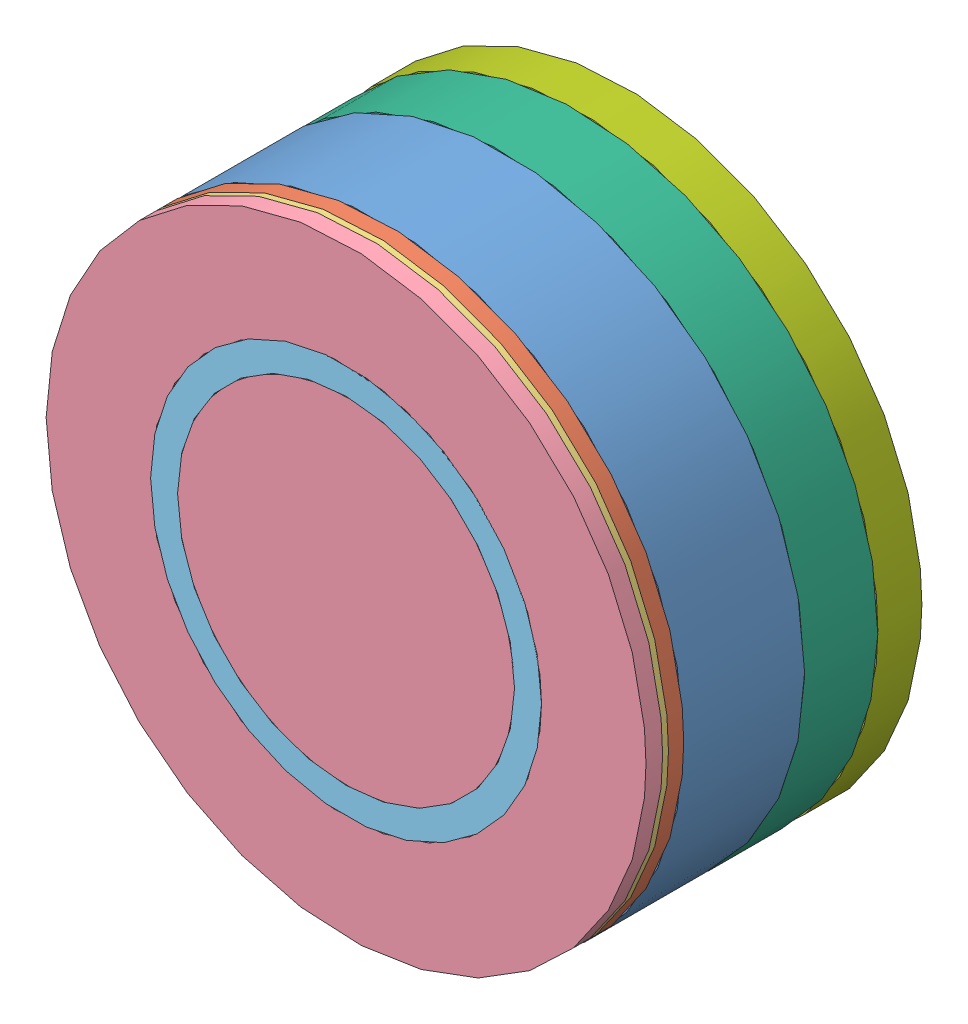
SolidWorks assembly ETA_3, configuration Default. Lengths in mm.
Overall size (348.91 348.91 122.8).
7 component instances, 7 part files, 12 mates.
Components (placement in the parent):
- B_m-2: B_m [Default] at (144.8274 154.4854 158.683) size (267 267 53.8)
- Ba_m-3: Ba_m [Default] at (144.8274 154.4854 212.483) size (267 267 6.8)
- Pr_m-2: Pr_m [Default] at (144.8274 154.4854 219.283) size (267 267 2.6)
- Bi_4_m-2: Bi_4_m [Default] at (144.8274 154.4854 221.883) size (267 267 7.4)
- Si_3-2: Si_3 [Default] at (144.8274 154.4854 148.183) size (174 174 81.1)
- Cr_m-1: Cr_m [Default] at (144.8274 154.4854 158.683) x (-0.923728 -0.383049 0) z (0 0 -1) size (267 267 38.1)
- Al-1: Al [Default] at (144.8274 154.4854 106.483) size (267 267 19.6)
Mates (geometry in assembly coordinates):
- Coincident29: coincident anti-aligned: plane of B_m-2 through (144.8274 154.4854 212.483) normal (0 0 1); plane of Ba_m-3 through (144.8274 154.4854 212.483) normal (0 0 -1)
- Coincident30: coincident aligned: circle of B_m-2; circle of Ba_m-3
- Coincident31: coincident anti-aligned: plane of Ba_m-3 through (144.8274 154.4854 219.283) normal (0 0 1); plane of Pr_m-2 through (144.8274 154.4854 219.283) normal (0 0 -1)
- Coincident32: coincident aligned: circle of Ba_m-3; circle of Pr_m-2
- Coincident33: coincident anti-aligned: plane of Pr_m-2 through (144.8274 154.4854 221.883) normal (0 0 1); plane of Bi_4_m-2 through (144.8274 154.4854 221.883) normal (0 0 -1)
- Coincident34: coincident aligned: circle of Pr_m-2; circle of Bi_4_m-2
- Coincident35: coincident aligned: plane of Bi_4_m-2 through (144.8274 154.4854 229.283) normal (0 0 1); plane of Si_3-2 through (144.8274 154.4854 229.283) normal (0 0 1)
- Coincident36: coincident aligned: circle of Bi_4_m-2; circle of Si_3-2
- Coincident37: coincident anti-aligned: plane of B_m-2 through (144.8274 154.4854 158.683) normal (0 0 -1); plane of Cr_m-1 through (144.8274 154.4854 158.683) normal (0 0 1)
- Coincident38: coincident anti-aligned: circle of B_m-2; circle of Cr_m-1
- Coincident39: coincident anti-aligned: plane of Cr_m-1 through (144.8274 154.4854 126.083) normal (0 0 -1); plane of Al-1 through (144.8274 154.4854 126.083) normal (0 0 1)
- Coincident40: coincident anti-aligned: circle of Cr_m-1; circle of Al-1
